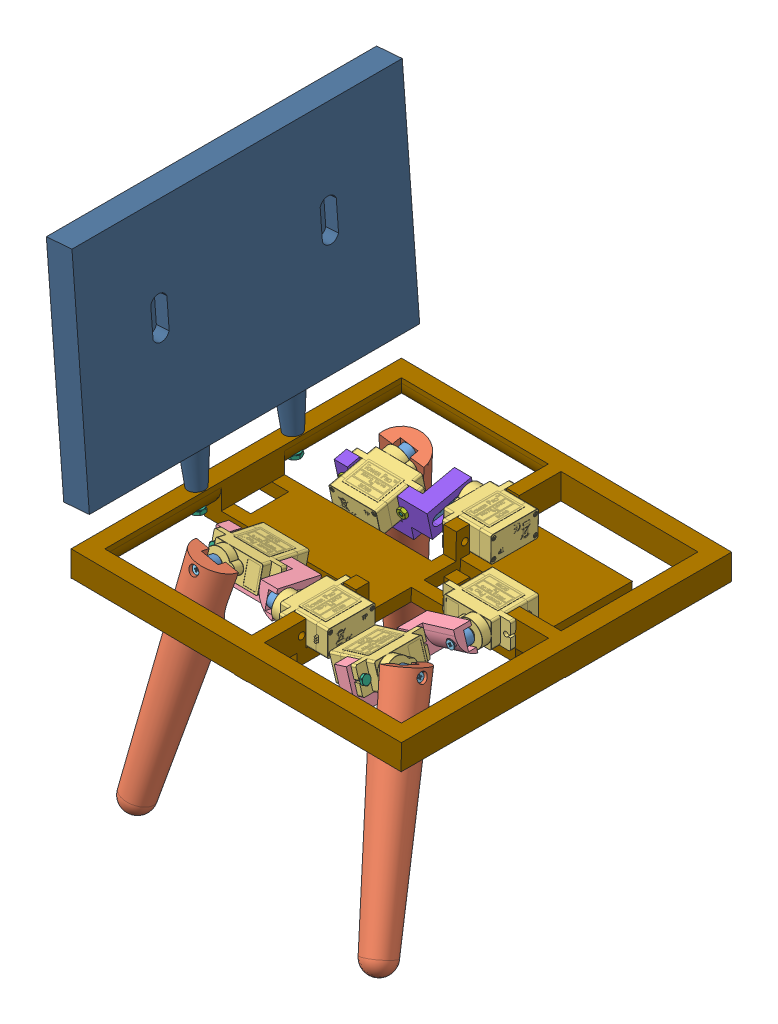
SolidWorks assembly main, configuration Default. Lengths in mm.
Overall size (174.75 233.66 173.65).
42 component instances, 10 part files, 98 mates.
Components (placement in the parent):
- SG90 - Micro Servo 9g - Tower Pro.2-2: SG90 - Micro Servo 9g - Tower Pro.2 [Peça] at (-71.4131 39.5425 72.6822) x (0.168542 0.962781 -0.211296) z (0.985693 -0.16503 0.034278) size (19.5 3.8 6.9)
- leg-2: leg [ﾃﾞﾌｫﾙﾄ] at (-87.693 -54.2274 89.3709) x (0.985693 -0.16503 0.034278) z (0.001868 0.214051 0.976821) size (23.99 107 23.99)
- SG90 - Micro Servo 9g - Tower Pro.1-2: SG90 - Micro Servo 9g - Tower Pro.1 [Peça] at (-66.3027 34.9811 52.0713) x (0.999962 -0.008727 0) z (-0.008524 -0.976784 0.214059) size (32.1 29.95 12.4)
- axis-1: axis [ﾃﾞﾌｫﾙﾄ] at (-49.8519 24.12 59.692) x (-0.999962 0.008727 0) z (-0.008524 -0.976784 0.214059) size (44.1 21.44 18.2)
- SG90 - Micro Servo 9g - Tower Pro.2-3: SG90 - Micro Servo 9g - Tower Pro.2 [Peça] at (-43.5266 38.4512 68.813) x (0.001868 0.214051 0.976821) z (-0.008524 -0.976784 0.214059) size (19.5 3.8 6.9)
- SG90 - Micro Servo 9g - Tower Pro.1-3: SG90 - Micro Servo 9g - Tower Pro.1 [Peça] at (-22.4274 38.2671 63.663) x (0 0 -1) z (0.008727 0.999962 0) size (32.1 29.95 12.4)
- cross recessed countersunk head screw_jis-1: cross recessed countersunk head screw_jis [JIS 1111 Cross recessed countersunk head screw - M2 x 8 - Z --8N] at (-71.4035 40.6456 77.7163) x (-0.001868 -0.214051 -0.976821) z (0.999998 -0.000202 -0.001868) size (8 3.8 3.8)
- cross recessed countersunk head screw_jis-2: cross recessed countersunk head screw_jis [JIS 1111 Cross recessed countersunk head screw - M2 x 8 - Z --8N] at (-47.78 38.4884 68.813) x (0.999962 -0.008727 0) z (-0.000049 -0.00567 0.999984) size (8 3.8 3.8)
- continuous thread hexagon head bolt_a_jis-1: continuous thread hexagon head bolt_a_jis [JIS B 1180 Continuous thread hexagon head bolt A M2 x 10 --N] at (-80.1853 37.0396 60.9115) x (-0.001868 -0.214051 -0.976821) z (0.999998 -0.000202 -0.001868) size (11.4 4.62 4)
- continuous thread hexagon head bolt_a_jis-2: continuous thread hexagon head bolt_a_jis [JIS B 1180 Continuous thread hexagon head bolt A M2 x 10 --N] at (-52.3863 36.797 60.9115) x (-0.001868 -0.214051 -0.976821) z (0.999998 -0.000202 -0.001868) size (11.4 4.62 4) (hidden)
- hexagon nut style 1_ab_jis-7: hexagon nut style 1_ab_jis [JIS B 1181 Hexagon nut - style 1 A M2 - D --N] at (-52.4048 34.6779 51.241) x (0.999998 -0.000202 -0.001868) z (0.001868 0.214051 0.976821) size (4 4.62 1.6)
- hexagon nut style 1_ab_jis-8: hexagon nut style 1_ab_jis [JIS B 1181 Hexagon nut - style 1 A M2 - D --N] at (-80.2038 34.9205 51.241) x (0.999998 -0.000202 -0.001868) z (0.001868 0.214051 0.976821) size (4 4.62 1.6)
- axis_mirror-1: axis_mirror [ﾃﾞﾌｫﾙﾄ] at (-49.8745 21.5284 1.8371) x (-0.999962 0.008727 0) z (-0.008522 -0.976547 -0.215136) size (44.1 21.44 18.2)
- SG90 - Micro Servo 9g - Tower Pro.1-4: SG90 - Micro Servo 9g - Tower Pro.1 [Peça] at (-22.4274 38.2671 -13.837) x (0 0 1) z (-0.008727 -0.999962 0) size (32.1 29.95 12.4)
- SG90 - Micro Servo 9g - Tower Pro.2-4: SG90 - Micro Servo 9g - Tower Pro.2 [Peça] at (-43.5266 38.4512 -18.987) x (0.001877 0.215128 -0.976584) z (0.008522 0.976547 0.215136) size (19.5 3.8 6.9)
- SG90 - Micro Servo 9g - Tower Pro.1-5: SG90 - Micro Servo 9g - Tower Pro.1 [Peça] at (-65.8029 34.9583 -2.2493) x (0.999962 -0.008727 0) z (0.008522 0.976547 0.215136) size (32.1 29.95 12.4)
- SG90 - Micro Servo 9g - Tower Pro.2-5: SG90 - Micro Servo 9g - Tower Pro.2 [Peça] at (-70.9131 39.5424 -22.8552) x (0.193663 0.958019 0.21141) z (-0.981066 0.189525 0.039864) size (19.5 3.8 6.9)
- leg-3: leg [ﾃﾞﾌｫﾙﾄ] at (-89.6184 -53.7718 -39.5559) x (-0.981066 0.189525 0.039864) z (0.001877 0.215128 -0.976584) size (23.99 107 23.99)
- cross recessed countersunk head screw_jis-3: cross recessed countersunk head screw_jis [JIS 1111 Cross recessed countersunk head screw - M2 x 8 - Z --8N] at (-70.9028 40.7272 -28.2334) x (-0.001877 -0.215128 0.976584) z (-0.455748 -0.869083 -0.192323) size (8 3.8 3.8)
- cross recessed countersunk head screw_jis-5: cross recessed countersunk head screw_jis [JIS 1111 Cross recessed countersunk head screw - M2 x 8 - Z --8N] at (-48.1335 38.4914 -18.987) x (0.999962 -0.008727 0) z (0 0 1) size (8 3.8 3.8)
- continuous thread hexagon head bolt_a_jis-3: continuous thread hexagon head bolt_a_jis [JIS B 1180 Continuous thread hexagon head bolt A M2 x 10 --N] at (-51.8864 36.7839 -11.0874) x (-0.001877 -0.215128 0.976584) z (-0.923912 -0.373271 -0.084002) size (11.4 4.62 4)
- continuous thread hexagon head bolt_a_jis-4: continuous thread hexagon head bolt_a_jis [JIS B 1180 Continuous thread hexagon head bolt A M2 x 10 --N] at (-79.6854 37.0265 -11.0874) x (-0.001877 -0.215128 0.976584) z (-0.923912 -0.373271 -0.084002) size (11.4 4.62 4)
- hexagon nut style 1_ab_jis-5: hexagon nut style 1_ab_jis [JIS B 1181 Hexagon nut - style 1 A M2 - D --N] at (-51.908 34.3099 0.1433) x (0.999998 -0.000353 0.001845) z (-0.001877 -0.215128 0.976584) size (4 4.62 1.6)
- hexagon nut style 1_ab_jis-6: hexagon nut style 1_ab_jis [JIS B 1181 Hexagon nut - style 1 A M2 - D --N] at (-79.707 34.5525 0.1433) x (0.999998 -0.000204 0.001877) z (-0.001877 -0.215128 0.976584) size (4 4.62 1.6)
- SG90 - Micro Servo 9g - Tower Pro.2-7: SG90 - Micro Servo 9g - Tower Pro.2 [Peça] at (20.8121 39.0708 68.813) x (-0.268009 0.885096 -0.380495) z (0.11027 -0.364166 -0.924783) size (19.5 3.8 6.9)
- leg-4: leg [ﾃﾞﾌｫﾙﾄ] at (43.0515 -47.4865 105.5498) x (0.11027 -0.364166 -0.924783) z (0.957085 0.289808 0) size (23.99 107 23.99)
- SG90 - Micro Servo 9g - Tower Pro.1-7: SG90 - Micro Servo 9g - Tower Pro.1 [Peça] at (0.6176 32.9558 63.663) x (0 0 -1) z (0.289808 -0.957085 0) size (32.1 29.95 12.4)
- axis-3: axis [ﾃﾞﾌｫﾙﾄ] at (9.0533 22.8676 47.618) x (0 0 1) z (0.289808 -0.957085 0) size (44.1 21.44 18.2)
- SG90 - Micro Servo 9g - Tower Pro.2-8: SG90 - Micro Servo 9g - Tower Pro.2 [Peça] at (17.0211 37.9229 41.418) x (0.957085 0.289808 0) z (0.289808 -0.957085 0) size (19.5 3.8 6.9)
- SG90 - Micro Servo 9g - Tower Pro.1-8: SG90 - Micro Servo 9g - Tower Pro.1 [Peça] at (11.8713 37.9678 20.318) x (-0.999962 0.008727 0) z (0.008727 0.999962 0) size (32.1 29.95 12.4)
- cross recessed countersunk head screw_jis-6: cross recessed countersunk head screw_jis [JIS 1111 Cross recessed countersunk head screw - M2 x 8 - Z --8N] at (25.7445 40.5643 68.813) x (-0.957085 -0.289808 0) z (-0.002 0.006605 -0.999976) size (8 3.8 3.8)
- cross recessed countersunk head screw_jis-7: cross recessed countersunk head screw_jis [JIS 1111 Cross recessed countersunk head screw - M2 x 8 - Z --8N] at (17.0211 37.9229 45.6716) x (0 0 -1) z (0.999813 -0.019329 0) size (8 3.8 3.8)
- continuous thread hexagon head bolt_a_jis-5: continuous thread hexagon head bolt_a_jis [JIS B 1180 Continuous thread hexagon head bolt A M2 x 10 --N] at (9.2792 35.5786 77.563) x (-0.957085 -0.289808 0) z (-0.002 0.006605 -0.999976) size (11.4 4.62 4)
- continuous thread hexagon head bolt_a_jis-6: continuous thread hexagon head bolt_a_jis [JIS B 1180 Continuous thread hexagon head bolt A M2 x 10 --N] at (9.2792 35.5786 49.763) x (-0.957085 -0.289808 0) z (-0.004507 0.014883 -0.999879) size (11.4 4.62 4) (hidden)
- hexagon nut style 1_ab_jis-11: hexagon nut style 1_ab_jis [JIS B 1181 Hexagon nut - style 1 A M2 - D --N] at (-0.1959 32.7095 49.763) x (-0.004507 0.014883 -0.999879) z (0.957085 0.289808 0) size (4 4.62 1.6)
- hexagon nut style 1_ab_jis-12: hexagon nut style 1_ab_jis [JIS B 1181 Hexagon nut - style 1 A M2 - D --N] at (-0.1959 32.7095 77.563) x (-0.004507 0.014883 -0.999879) z (0.957085 0.289808 0) size (4 4.62 1.6)
- seat-1: seat [ﾃﾞﾌｫﾙﾄ] at (-27.0054 32.2068 24.913) x (0.999962 -0.008727 0) z (0 0 1) size (156.82 18.2 158.51)
- face-1: face [ﾃﾞﾌｫﾙﾄ] at (-112.8944 114.9951 24.913) x (0 0 -1) z (0.078459 -0.996917 0) size (156.75 12.2 123.27)
- continuous thread hexagon head bolt_a_jis-9: continuous thread hexagon head bolt_a_jis [JIS B 1180 Continuous thread hexagon head bolt A M3 x 20 --N] at (-100.4865 35.0862 2.038) x (-0.078459 0.996917 0) z (0.793347 0.062438 0.60556) size (22 6.35 5.5)
- continuous thread hexagon head bolt_a_jis-10: continuous thread hexagon head bolt_a_jis [JIS B 1180 Continuous thread hexagon head bolt A M3 x 20 --N] at (-100.4865 35.0862 47.788) x (-0.078459 0.996917 0) z (-0.539587 -0.042466 0.840858) size (22 6.35 5.5)
- hexagon nut style 1_ab_jis-15: hexagon nut style 1_ab_jis [JIS B 1181 Hexagon nut - style 1 A M3 - D --N] at (-102.0557 55.0246 2.038) x (0.993844 0.078217 -0.078459) z (0.078459 -0.996917 0) size (5.5 6.35 2.4)
- hexagon nut style 1_ab_jis-16: hexagon nut style 1_ab_jis [JIS B 1181 Hexagon nut - style 1 A M3 - D --N] at (-102.0557 55.0246 47.788) x (0.993844 0.078217 -0.078459) z (0.078459 -0.996917 0) size (5.5 6.35 2.4)
Mates (geometry in assembly coordinates):
- 同心円3: concentric anti-aligned: circle of SG90 - Micro Servo 9g - Tower Pro.2-2; circle of leg-2
- 一致1: coincident anti-aligned: plane of SG90 - Micro Servo 9g - Tower Pro.2-2 through (-71.4131 39.5425 72.6822) normal (0.001868 0.214051 0.976821); plane of leg-2 through (-71.4131 39.5425 72.6822) normal (-0.001868 -0.214051 -0.976821)
- 平行1: parallel anti-aligned: plane of SG90 - Micro Servo 9g - Tower Pro.2-2 through (-75.7706 25.9403 74.2379) normal (-0.99342 0.112254 -0.022699); plane of leg-2 through (-74.9392 34.695 59.1199) normal (0.99342 -0.112254 0.022699)
- 平行2: parallel anti-aligned: plane of SG90 - Micro Servo 9g - Tower Pro.2-2 through (-69.176 36.6787 71.8722) normal (0.975029 -0.217315 0.045756); plane of leg-2 through (-68.748 33.6585 59.3352) normal (-0.975029 0.217315 -0.045756)
- 同心円4: concentric aligned: circle of SG90 - Micro Servo 9g - Tower Pro.2-2; circle of SG90 - Micro Servo 9g - Tower Pro.1-2
- 一致2: coincident anti-aligned: plane of SG90 - Micro Servo 9g - Tower Pro.2-2 through (-71.4165 39.1572 70.9239) normal (-0.001868 -0.214051 -0.976821); plane of SG90 - Micro Servo 9g - Tower Pro.1-2 through (-71.4165 39.1572 70.9239) normal (0.001868 0.214051 0.976821)
- 一致7: coincident anti-aligned: plane of SG90 - Micro Servo 9g - Tower Pro.1-2 through (-76.7447 30.2159 58.4076) normal (-0.008524 -0.976784 0.214059); plane of axis-1 through (-77.6359 28.9392 52.5467) normal (0.008524 0.976784 -0.214059)
- 一致8: coincident anti-aligned: plane of SG90 - Micro Servo 9g - Tower Pro.1-2 through (-81.5373 31.088 58.2257) normal (-0.001868 -0.214051 -0.976821); plane of axis-1 through (-49.8519 24.12 59.692) normal (0.001868 0.214051 0.976821)
- 距離2: distance = 0.03 mm anti-aligned: plane of SG90 - Micro Servo 9g - Tower Pro.1-2 through (-77.5874 31.0535 58.2257) normal (-0.999962 0.008727 0); plane of axis-1 through (-77.5319 40.856 49.9352) normal (0.999962 -0.008727 0)
- 一致9: coincident aligned: plane of axis-1 through (-39.8523 24.0327 59.692) normal (0.999962 -0.008727 0); plane of SG90 - Micro Servo 9g - Tower Pro.2-3 through (-39.7267 38.4181 68.813) normal (0.999962 -0.008727 0)
- 一致10: coincident aligned: line of axis-1 through (-39.7203 39.1568 72.184) axis (-0.001868 -0.214051 -0.976821); line of SG90 - Micro Servo 9g - Tower Pro.2-3 through (-39.7203 39.1566 72.183) axis (-0.001868 -0.214051 -0.976821)
- 一致15: coincident: point of SG90 - Micro Servo 9g - Tower Pro.2-3
- 同心円6: concentric aligned: circle of SG90 - Micro Servo 9g - Tower Pro.2-3; circle of SG90 - Micro Servo 9g - Tower Pro.1-3
- 一致16: coincident anti-aligned: plane of SG90 - Micro Servo 9g - Tower Pro.2-3 through (-41.7266 38.4355 68.813) normal (0.999962 -0.008727 0); plane of SG90 - Micro Servo 9g - Tower Pro.1-3 through (-41.7266 38.4355 68.813) normal (-0.999962 0.008727 0)
- 同心円8: concentric anti-aligned: circle of leg-2; circle of cross recessed countersunk head screw_jis-1
- 一致19: coincident aligned: plane of leg-2 through (-71.4055 40.4201 76.6871) normal (0.001868 0.214051 0.976821); circle of cross recessed countersunk head screw_jis-1
- 同心円9: concentric anti-aligned: circle of axis-1; circle of cross recessed countersunk head screw_jis-2
- 一致20: coincident aligned: plane of axis-1 through (-46.7265 38.4792 68.813) normal (-0.999962 0.008727 0); circle of cross recessed countersunk head screw_jis-2
- 同心円16: concentric aligned: circle of SG90 - Micro Servo 9g - Tower Pro.1-2; circle of continuous thread hexagon head bolt_a_jis-2
- 一致21: coincident anti-aligned: plane of SG90 - Micro Servo 9g - Tower Pro.1-2 through (-81.5326 31.6231 60.6677) normal (0.001868 0.214051 0.976821); plane of continuous thread hexagon head bolt_a_jis-2 through (-52.3894 38.7532 59.0496) normal (-0.001868 -0.214051 -0.976821)
- 同心円17: concentric aligned: circle of SG90 - Micro Servo 9g - Tower Pro.1-2; circle of continuous thread hexagon head bolt_a_jis-1
- 一致22: coincident anti-aligned: plane of SG90 - Micro Servo 9g - Tower Pro.1-2 through (-81.5326 31.6231 60.6677) normal (0.001868 0.214051 0.976821); circle of continuous thread hexagon head bolt_a_jis-1
- 一致29: coincident aligned: plane of SG90 - Micro Servo 9g - Tower Pro.1-4 through (-27.6304 32.2123 -24.237) normal (-0.008727 -0.999962 0)
- 同心円22: concentric aligned: circle of SG90 - Micro Servo 9g - Tower Pro.1-4; circle of SG90 - Micro Servo 9g - Tower Pro.2-4
- 一致30: coincident anti-aligned: plane of SG90 - Micro Servo 9g - Tower Pro.1-4 through (-41.7266 38.4355 -18.987) normal (-0.999962 0.008727 0); plane of SG90 - Micro Servo 9g - Tower Pro.2-4 through (-41.7266 38.4355 -18.987) normal (0.999962 -0.008727 0)
- 同心円23: concentric anti-aligned: circle of axis_mirror-1; circle of SG90 - Micro Servo 9g - Tower Pro.2-4
- 一致32: coincident anti-aligned: plane of axis_mirror-1 through (-43.5266 38.4512 -18.987) normal (0.999962 -0.008727 0); plane of SG90 - Micro Servo 9g - Tower Pro.2-4 through (-43.5266 38.4512 -18.987) normal (-0.999962 0.008727 0)
- 平行4: parallel aligned: line of axis_mirror-1 through (-39.7321 37.8039 -4.5957) axis (0.00234 0.268089 -0.963391); line of SG90 - Micro Servo 9g - Tower Pro.2-4 through (-42.1362 37.3432 -4.7298) axis (0.00234 0.268089 -0.963391)
- 一致36: coincident anti-aligned: plane of axis_mirror-1 through (-77.636 28.9213 -2.7315) normal (0.008522 0.976547 0.215136); plane of SG90 - Micro Servo 9g - Tower Pro.1-5 through (-76.2448 30.2 -8.5911) normal (-0.008522 -0.976547 -0.215136)
- 一致37: coincident anti-aligned: plane of axis_mirror-1 through (-49.852 24.11 -9.8819) normal (0.001877 0.215128 -0.976584); plane of SG90 - Micro Servo 9g - Tower Pro.1-5 through (-80.9479 41.3257 -6.1493) normal (-0.001877 -0.215128 0.976584)
- 同心円24: concentric anti-aligned: circle of axis_mirror-1; circle of SG90 - Micro Servo 9g - Tower Pro.1-5
- 一致40: coincident aligned: line of SG90 - Micro Servo 9g - Tower Pro.1-3 through (-11.9301 32.1753 74.063) axis (0 0 -1); line of SG90 - Micro Servo 9g - Tower Pro.1-4 through (-11.9301 32.1753 -3.437) axis (0 0 -1)
- 同心円25: concentric anti-aligned: circle of SG90 - Micro Servo 9g - Tower Pro.1-5; circle of SG90 - Micro Servo 9g - Tower Pro.2-5
- 一致41: coincident anti-aligned: plane of SG90 - Micro Servo 9g - Tower Pro.1-5 through (-70.9165 39.1552 -21.0974) normal (0.001877 0.215128 -0.976584); plane of SG90 - Micro Servo 9g - Tower Pro.2-5 through (-70.9165 39.1552 -21.0974) normal (-0.001877 -0.215128 0.976584)
- 同心円26: concentric aligned: circle of SG90 - Micro Servo 9g - Tower Pro.2-5; circle of leg-3
- 一致43: coincident anti-aligned: plane of SG90 - Micro Servo 9g - Tower Pro.2-5 through (-70.9131 39.5424 -22.8552) normal (0.001877 0.215128 -0.976584); plane of leg-3 through (-70.9131 39.5424 -22.8552) normal (-0.001877 -0.215128 0.976584)
- 平行6: parallel aligned: line of SG90 - Micro Servo 9g - Tower Pro.2-5 through (-75.617 26.055 -24.4018) axis (0.139847 0.966933 0.21327); line of leg-3 through (-75.9865 26.5067 -21.8455) axis (0.139847 0.966933 0.21327)
- 一致46: coincident anti-aligned: plane of leg-3 through (-70.9054 40.4245 -26.8592) normal (0.001877 0.215128 -0.976584); circle of cross recessed countersunk head screw_jis-3
- 同心円29: concentric anti-aligned: circle of leg-3; circle of cross recessed countersunk head screw_jis-3
- 一致47: coincident anti-aligned: plane of axis_mirror-1 through (-46.7265 38.4792 -18.987) normal (-0.999962 0.008727 0); circle of cross recessed countersunk head screw_jis-5
- 同心円30: concentric aligned: circle of axis_mirror-1; circle of cross recessed countersunk head screw_jis-5
- 同心円31: concentric aligned: circle of SG90 - Micro Servo 9g - Tower Pro.1-5; circle of continuous thread hexagon head bolt_a_jis-3
- 一致48: coincident anti-aligned: plane of SG90 - Micro Servo 9g - Tower Pro.1-5 through (-80.9432 41.8635 -8.5907) normal (0.001877 0.215128 -0.976584); plane of continuous thread hexagon head bolt_a_jis-3 through (-52.7726 38.5668 -9.2628) normal (-0.001877 -0.215128 0.976584)
- 同心円32: concentric aligned: circle of SG90 - Micro Servo 9g - Tower Pro.1-5; circle of continuous thread hexagon head bolt_a_jis-4
- 一致49: coincident anti-aligned: plane of SG90 - Micro Servo 9g - Tower Pro.1-5 through (-80.9432 41.8635 -8.5907) normal (0.001877 0.215128 -0.976584); plane of continuous thread hexagon head bolt_a_jis-4 through (-80.5716 38.8094 -9.2628) normal (-0.001877 -0.215128 0.976584)
- 同心円33: concentric anti-aligned: circle of continuous thread hexagon head bolt_a_jis-3; circle of hexagon nut style 1_ab_jis-5
- 一致51: coincident anti-aligned: plane of axis_mirror-1 through (-49.8632 22.8192 -4.0224) normal (-0.001877 -0.215128 0.976584); plane of hexagon nut style 1_ab_jis-5 through (-51.9051 36.9095 -0.9224) normal (0.001877 0.215128 -0.976584)
- 同心円34: concentric anti-aligned: circle of continuous thread hexagon head bolt_a_jis-4; circle of hexagon nut style 1_ab_jis-6
- 一致53: coincident anti-aligned: plane of axis_mirror-1 through (-49.8632 22.8192 -4.0224) normal (-0.001877 -0.215128 0.976584); plane of hexagon nut style 1_ab_jis-6 through (-79.7044 37.1521 -0.9224) normal (0.001877 0.215128 -0.976584)
- 同心円35: concentric aligned: circle of continuous thread hexagon head bolt_a_jis-1; circle of hexagon nut style 1_ab_jis-8
- 一致55: coincident anti-aligned: plane of axis-1 through (-49.8631 22.8357 53.8311) normal (-0.001868 -0.214051 -0.976821); plane of hexagon nut style 1_ab_jis-8 through (-80.2042 37.1763 50.7466) normal (0.001868 0.214051 0.976821)
- 同心円36: concentric aligned: circle of continuous thread hexagon head bolt_a_jis-2; circle of hexagon nut style 1_ab_jis-7
- 一致57: coincident anti-aligned: plane of axis-1 through (-49.8631 22.8357 53.8311) normal (-0.001868 -0.214051 -0.976821); plane of hexagon nut style 1_ab_jis-7 through (-52.4053 36.9337 50.7466) normal (0.001868 0.214051 0.976821)
- 同心円39: concentric anti-aligned: circle of SG90 - Micro Servo 9g - Tower Pro.2-7; circle of leg-4
- 平行7: parallel anti-aligned: plane of SG90 - Micro Servo 9g - Tower Pro.2-7 through (20.3565 35.7448 67.2029) normal (0.124729 -0.411915 -0.902645); plane of leg-4 through (8.1218 31.6647 66.8202) normal (-0.124729 0.411915 0.902645)
- 一致60: coincident aligned: plane of axis-3 through (17.0211 37.9229 44.618) normal (0 0 1); circle of cross recessed countersunk head screw_jis-7
- 同心円40: concentric aligned: circle of SG90 - Micro Servo 9g - Tower Pro.1-7; circle of continuous thread hexagon head bolt_a_jis-6
- 一致61: coincident anti-aligned: plane of SG90 - Micro Servo 9g - Tower Pro.2-7 through (19.0894 38.5491 68.813) normal (-0.957085 -0.289808 0); plane of SG90 - Micro Servo 9g - Tower Pro.1-7 through (19.0894 38.5491 68.813) normal (0.957085 0.289808 0)
- 一致62: coincident anti-aligned: plane of SG90 - Micro Servo 9g - Tower Pro.2-8 through (17.0211 37.9229 39.618) normal (0 0 -1); plane of SG90 - Micro Servo 9g - Tower Pro.1-8 through (17.0211 37.9229 39.618) normal (0 0 1)
- 一致63: coincident anti-aligned: plane of SG90 - Micro Servo 9g - Tower Pro.1-7 through (9.4608 30.1482 78.863) normal (0.957085 0.289808 0); plane of continuous thread hexagon head bolt_a_jis-6 through (7.2701 37.3829 49.7989) normal (-0.957085 -0.289808 0)
- 同心円41: concentric aligned: circle of SG90 - Micro Servo 9g - Tower Pro.1-7; circle of continuous thread hexagon head bolt_a_jis-5
- 一致64: coincident anti-aligned: plane of SG90 - Micro Servo 9g - Tower Pro.1-7 through (9.4608 30.1482 78.863) normal (0.957085 0.289808 0); circle of continuous thread hexagon head bolt_a_jis-5
- 同心円42: concentric aligned: circle of SG90 - Micro Servo 9g - Tower Pro.2-7; circle of SG90 - Micro Servo 9g - Tower Pro.1-7
- 一致65: coincident anti-aligned: plane of SG90 - Micro Servo 9g - Tower Pro.1-7 through (7.0681 29.4236 78.863) normal (-0.957085 -0.289808 0); plane of axis-3 through (9.0533 22.8676 47.618) normal (0.957085 0.289808 0)
- 一致66: coincident aligned: plane of axis-3 through (9.0533 22.8676 37.618) normal (0 0 -1); plane of SG90 - Micro Servo 9g - Tower Pro.2-8 through (17.0211 37.9229 37.618) normal (0 0 -1)
- 一致67: coincident aligned: plane of leg-4 through (24.7362 40.259 68.813) normal (0.957085 0.289808 0); circle of cross recessed countersunk head screw_jis-6
- 一致68: coincident anti-aligned: plane of SG90 - Micro Servo 9g - Tower Pro.2-7 through (20.8121 39.0708 68.813) normal (0.957085 0.289808 0); plane of leg-4 through (20.8121 39.0708 68.813) normal (-0.957085 -0.289808 0)
- 同心円43: concentric anti-aligned: circle of axis-3; circle of cross recessed countersunk head screw_jis-7
- 一致69: coincident aligned: line of axis-3 through (20.324 38.923 37.618) axis (-0.957085 -0.289808 0); line of SG90 - Micro Servo 9g - Tower Pro.2-8 through (20.3231 38.9227 37.618) axis (-0.957085 -0.289808 0)
- 平行8: parallel anti-aligned: plane of SG90 - Micro Servo 9g - Tower Pro.2-7 through (23.0468 26.8601 76.0473) normal (-0.095483 0.315332 0.944166); plane of leg-4 through (7.4292 33.9521 72.6289) normal (0.095483 -0.315332 -0.944166)
- 一致70: coincident anti-aligned: plane of SG90 - Micro Servo 9g - Tower Pro.1-7 through (7.3144 28.6101 74.063) normal (0.289808 -0.957085 0); plane of axis-3 through (1.5719 26.8713 75.443) normal (-0.289808 0.957085 0)
- 同心円45: concentric aligned: circle of SG90 - Micro Servo 9g - Tower Pro.2-8; circle of SG90 - Micro Servo 9g - Tower Pro.1-8
- 同心円46: concentric anti-aligned: circle of leg-4; circle of cross recessed countersunk head screw_jis-6
- 一致72: coincident anti-aligned: plane of axis-3 through (3.3108 21.1288 47.618) normal (-0.957085 -0.289808 0); plane of hexagon nut style 1_ab_jis-12 through (-0.8651 34.9195 77.5989) normal (0.957085 0.289808 0)
- 同心円48: concentric aligned: circle of continuous thread hexagon head bolt_a_jis-6; circle of hexagon nut style 1_ab_jis-11
- 同心円49: concentric aligned: circle of continuous thread hexagon head bolt_a_jis-5; circle of hexagon nut style 1_ab_jis-12
- 一致73: coincident anti-aligned: plane of axis-3 through (3.3108 21.1288 47.618) normal (-0.957085 -0.289808 0); plane of hexagon nut style 1_ab_jis-11 through (-0.8651 34.9195 49.7989) normal (0.957085 0.289808 0)
- 一致74: coincident aligned: plane of SG90 - Micro Servo 9g - Tower Pro.1-8 through (22.2177 31.7773 25.468) normal (-0.008727 -0.999962 0)
- 同心円51: concentric anti-aligned: circle of axis-3; circle of SG90 - Micro Servo 9g - Tower Pro.2-8
- 同心円52: concentric aligned: circle of axis-1; circle of SG90 - Micro Servo 9g - Tower Pro.2-3
- 一致77: coincident aligned: plane of SG90 - Micro Servo 9g - Tower Pro.1-3 through (-27.5314 43.5619 52.413) normal (0 0 -1); plane of SG90 - Micro Servo 9g - Tower Pro.1-7 through (7.0681 29.4236 52.413) normal (0 0 -1)
- 距離7: distance = 55 mm anti-aligned: plane of SG90 - Micro Servo 9g - Tower Pro.1-3 through (-27.5314 43.5619 52.413) normal (0 0 -1); plane of SG90 - Micro Servo 9g - Tower Pro.1-4 through (-27.623 33.0623 -2.587) normal (0 0 1)
- 距離8: distance = 12.5 mm anti-aligned: plane of SG90 - Micro Servo 9g - Tower Pro.1-8 through (0.6676 43.3158 25.468) normal (-0.999962 0.008727 0); plane of SG90 - Micro Servo 9g - Tower Pro.1-3 through (-11.832 43.4249 74.063) normal (0.999962 -0.008727 0)
- 一致79: coincident aligned: plane of seat-1 through (-27.6304 32.2123 74.958) normal (-0.008727 -0.999962 0)
- 距離9: distance = 20.3 mm anti-aligned: plane of SG90 - Micro Servo 9g - Tower Pro.1-8 through (23.1667 43.1194 25.468) normal (0.999962 -0.008727 0); plane of seat-1 through (43.4733 43.7922 -45.462) normal (-0.999962 0.008727 0)
- 距離10: distance = 20.375 mm anti-aligned: plane of seat-1 through (-97.2713 45.0205 95.288) normal (0 0 -1); plane of SG90 - Micro Servo 9g - Tower Pro.1-3 through (-27.5314 43.5619 74.913) normal (0 0 1)
- 同心円53: concentric anti-aligned: circle of seat-1; circle of face-1
- 同心円54: concentric anti-aligned: circle of seat-1; circle of face-1
- 一致85: coincident anti-aligned: plane of seat-1 through (-101.2711 45.0554 2.038) normal (-0.078459 0.996917 0); plane of face-1 through (-101.2711 45.0554 2.038) normal (0.078459 -0.996917 0)
- 一致86: coincident anti-aligned: plane of SG90 - Micro Servo 9g - Tower Pro.1-8 through (27.1166 43.085 25.468) normal (0 0 -1); plane of seat-1 through (23.1177 31.7694 25.468) normal (0 0 1)
- 同心円55: concentric aligned: circle of seat-1; circle of continuous thread hexagon head bolt_a_jis-9
- 一致87: coincident anti-aligned: plane of seat-1 through (-100.6435 37.0801 2.038) normal (0.078459 -0.996917 0); plane of continuous thread hexagon head bolt_a_jis-9 through (-102.5604 36.9292 4.565) normal (-0.078459 0.996917 0)
- 同心円56: concentric anti-aligned: cylinder of seat-1 through (-98.804 13.7075 47.788) axis (-0.078459 0.996917 0) radius 1.55; circle of continuous thread hexagon head bolt_a_jis-10
- 一致88: coincident anti-aligned: plane of seat-1 through (-100.6435 37.0801 47.788) normal (0.078459 -0.996917 0); plane of continuous thread hexagon head bolt_a_jis-10 through (-103.3053 36.8706 46.0693) normal (-0.078459 0.996917 0)
- 一致89: coincident anti-aligned: plane of face-1 through (-99.065 55.26 -1.462) normal (-0.078459 0.996917 0); plane of hexagon nut style 1_ab_jis-15 through (-101.8074 55.0441 5.2036) normal (0.078459 -0.996917 0)
- 同心円57: concentric anti-aligned: circle of face-1; circle of hexagon nut style 1_ab_jis-15
- 一致91: coincident anti-aligned: plane of face-1 through (-99.065 55.26 51.288) normal (-0.078459 0.996917 0); plane of hexagon nut style 1_ab_jis-16 through (-101.8074 55.0441 50.9536) normal (0.078459 -0.996917 0)
- 同心円58: concentric anti-aligned: circle of face-1; circle of hexagon nut style 1_ab_jis-16
